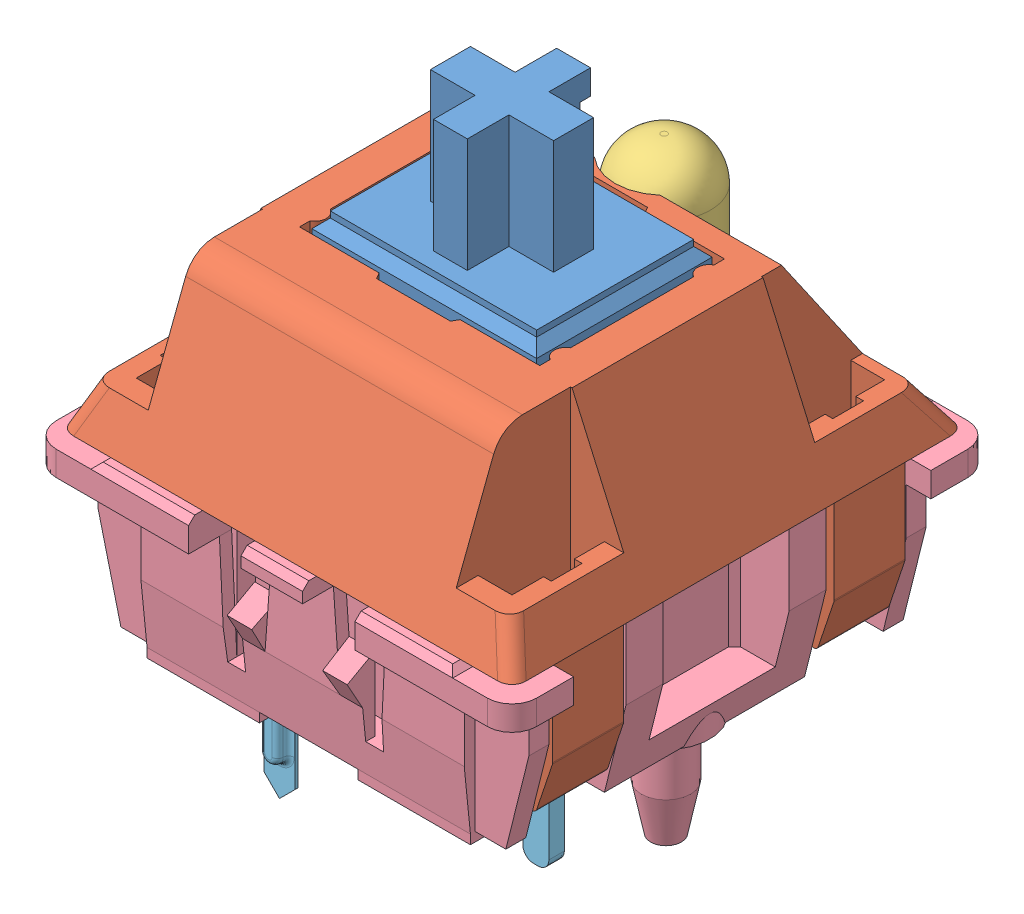
SolidWorks assembly MX 按键, configuration Default. Lengths in mm.
Overall size (15.6 18.9 15.6).
5 component instances, 5 part files, 8 mates.
Components (placement in the parent):
- MX 轴 按键-1: MX 轴 按键 [Default] at (7.35 2 -7.35) size (8.9 12.4 5.7)
- MX 轴 轴体-1: MX 轴 轴体 [Default] at origin size (14.7 9.9 14.7)
- MX轴 无帽LED-1: MX轴 无帽LED [Default] at (7.35 0.5 -12.292) size (3 15.3 3)
- MX轴 轴体 底部-1: MX轴 轴体 底部 [默认] at (7.35 -0.2 -7.35) size (15.6 12.5 15.6)
- 针脚-2: 针脚 [默认] at (-5.5727 -8.7 12.741) size (7.15 6.7 2.96)
Mates (geometry in assembly coordinates):
- Distance1: distance = 0.15 mm: plane of MX 轴 轴体-1 through (3.45 1.4 -4.35) normal (0 0 -1); plane of MX 轴 按键-1 through (3.7 5.2 -4.5) normal (0 0 1)
- Distance2: distance = 0.25 mm: plane of MX 轴 轴体-1 through (3.45 1.4 -10.35) normal (1 0 0); plane of MX 轴 按键-1 through (3.7 5.2 -10.2) normal (-1 0 0)
- Coincident4: coincident: plane of MX 轴 轴体-1 through (0 0 0) normal (0 -1 0); plane of MX轴 轴体 底部-1 through (7.35 0 -7.35) normal (0 1 0)
- LimitDistance2: limit distance = -0.5 mm: plane of MX 轴 按键-1 through (7.35 5.7 -7.35) normal (0 1 0); plane of MX 轴 轴体-1 through (0 5.2 0) normal (0 1 0)
- Coincident10: coincident: plane of MX轴 轴体 底部-1 through (10.6 -0.9 -4.95) normal (0 0 1); plane of 针脚-2 through (10.6 -2.5 -4.95) normal (0 0 -1)
- Coincident11: coincident: plane of MX轴 轴体 底部-1 through (10.6 -0.9 -4.95) normal (1 0 0); plane of 针脚-2 through (10.6 -2.5 -4.95) normal (-1 0 0)
- Concentric1: concentric: cylinder of MX 轴 轴体-1 through (7.35 0.5 -12.292) axis (0 1 0) radius 1.6; cylinder of MX轴 无帽LED-1 through (7.35 5.8 -12.292) axis (0 -1 0) radius 1.5
- Coincident12: coincident: plane of MX 轴 轴体-1 through (7.35 0.5 -12.292) normal (0 1 0); plane of MX轴 无帽LED-1 through (7.35 0.5 -12.292) normal (0 -1 0)
